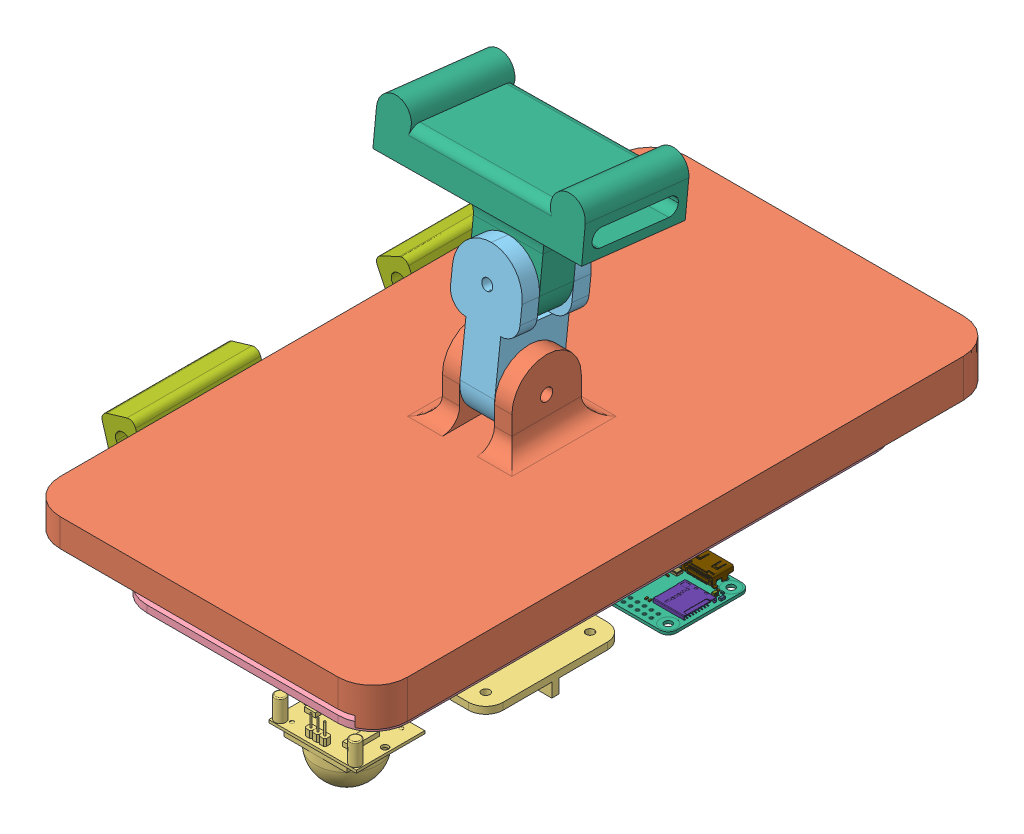
SolidWorks assembly Case_001, configuration Default. Lengths in mm.
Overall size (141.75 176.14 228.6).
95 component instances, 26 part files, 36 mates.
Components (placement in the parent):
- Top_001-2: Top_001 [Default] at (-101.6 0 -203.2) x (0 0 1) z (0 1 0) size (222.25 128.91 71.12) (hidden)
- Battery Mockup-1: Battery Mockup [Default] at (-90.805 45.72 -177.165) x (0 0 1) z (-1 0 0) size (171.45 22.86 80.01)
- Bottom_001-1: Bottom_001 [Default] at (12.7 73.66 12.7) x (-1 0 0) z (0 0 1) size (132.08 39.88 228.6)
- Camera Bracket-1: Camera Bracket [Default] at (-25.4 2.54 -66.675) x (0 0 -1) z (1 0 0) size (50.8 7.62 50.8)
- Separator-1: Separator [Default] at (-3.175 45.72 -3.175) x (0 -1 0) z (1 0 0) size (2.54 196.85 95.25)
- Cam V2.1 v1.step-1: Cam V2.1 v1.step [Default] at (-51.73 11.16 -89.4159) x (0 -1 0) z (1 0 0) size (6.48 24.01 25.01)
- RapberryPiZero.STEP-1: RapberryPiZero.STEP [Default] at (-102.4814 -13.0566 -128.6208) x (-1 0 0) z (0 0 -1) size (65 4.45 31.23)
  - Raspberry_pizero_PCB.STEP-1: Raspberry_pizero_PCB.STEP [Default] at (-51.2564 20.0966 13.0542) size (65 1 30)
  - Micro USB_input_female (short)-SMT.STEP-1: Micro USB_input_female (short)-SMT.STEP [Default] at (-42.3564 22.3216 26.5042) size (7.98 2.94 5.43)
  - Micro USB_input_female (short)-SMT.STEP-2: Micro USB_input_female (short)-SMT.STEP [Default] at (-29.7564 22.3216 26.5042) size (7.98 2.94 5.43)
  - 0204 - Capacitor.STEP-1: 0204 - Capacitor.STEP [Default] at (-62.4121 21.3466 11.2398) size (1 0.5 0.6)
  - 0204 - Capacitor.STEP-2: 0204 - Capacitor.STEP [Default] at (-62.4121 21.3466 12.2528) size (1 0.5 0.6)
  - 0204 - Capacitor.STEP-3: 0204 - Capacitor.STEP [Default] at (-61.8122 21.3466 13.3136) size (1 0.5 0.6)
  - 0204 - Capacitor.STEP-4: 0204 - Capacitor.STEP [Default] at (-61.8122 21.3466 14.2646) size (1 0.5 0.6)
  - 0204 - Capacitor.STEP-5: 0204 - Capacitor.STEP [Default] at (-61.8122 21.3466 15.241) size (1 0.5 0.6)
  - 0204 - Capacitor.STEP-6: 0204 - Capacitor.STEP [Default] at (-61.8122 21.3466 16.2144) size (1 0.5 0.6)
  - 0204 - Capacitor.STEP-7: 0204 - Capacitor.STEP [Default] at (-61.8122 21.3466 17.2416) size (1 0.5 0.6)
  - 0204 - Capacitor.STEP-8: 0204 - Capacitor.STEP [Default] at (-62.5919 21.3466 20.9695) size (1 0.5 0.6)
  - 0204 - Capacitor.STEP-9: 0204 - Capacitor.STEP [Default] at (-62.5919 21.3466 21.919) size (1 0.5 0.6)
  - 0204 - Capacitor.STEP-10: 0204 - Capacitor.STEP [Default] at (-60.4584 21.3466 22.3712) x (0 0 1) z (-1 0 0) size (1 0.5 0.6)
  - 0204 - Capacitor.STEP-11: 0204 - Capacitor.STEP [Default] at (-60.0807 21.3466 22.3712) x (0 0 -1) z (1 0 0) size (1 0.5 0.6)
  - 0204 - Capacitor.STEP-12: 0204 - Capacitor.STEP [Default] at (-59.0466 21.3466 22.3712) x (0 0 -1) z (1 0 0) size (1 0.5 0.6)
  - 0204 - Capacitor.STEP-13: 0204 - Capacitor.STEP [Default] at (-52.6496 21.3466 22.316) x (0 0 1) z (-1 0 0) size (1 0.5 0.6)
  - 0204 - Capacitor.STEP-14: 0204 - Capacitor.STEP [Default] at (-52.25 21.3466 22.316) x (0 0 -1) z (1 0 0) size (1 0.5 0.6)
  - 0204 - Capacitor.STEP-15: 0204 - Capacitor.STEP [Default] at (-51.2398 21.3466 22.316) x (0 0 -1) z (1 0 0) size (1 0.5 0.6)
  - 0204 - Capacitor.STEP-16: 0204 - Capacitor.STEP [Default] at (-49.1841 21.3466 22.316) x (0 0 -1) z (1 0 0) size (1 0.5 0.6)
  - 0204 - Capacitor.STEP-17: 0204 - Capacitor.STEP [Default] at (-48.1448 21.3466 22.316) x (0 0 -1) z (1 0 0) size (1 0.5 0.6)
  - 0204 - Capacitor.STEP-18: 0204 - Capacitor.STEP [Default] at (-46.475 21.3466 21.113) size (1 0.5 0.6)
  - 0204 - Capacitor.STEP-19: 0204 - Capacitor.STEP [Default] at (-45.7322 21.3466 20.0663) size (1 0.5 0.6)
  - 0204 - Capacitor.STEP-20: 0204 - Capacitor.STEP [Default] at (-45.7322 21.3466 19.0675) size (1 0.5 0.6)
  - 0204 - Capacitor.STEP-21: 0204 - Capacitor.STEP [Default] at (-45.7322 21.3466 18.1249) size (1 0.5 0.6)
  - 0204 - Capacitor.STEP-22: 0204 - Capacitor.STEP [Default] at (-45.7322 21.3466 17.1095) size (1 0.5 0.6)
  - 0204 - Capacitor.STEP-23: 0204 - Capacitor.STEP [Default] at (-46.3457 21.3466 16.1412) size (1 0.5 0.6)
  - 0204 - Capacitor.STEP-24: 0204 - Capacitor.STEP [Default] at (-46.3457 21.3466 15.1229) size (1 0.5 0.6)
  - 0204 - Capacitor.STEP-25: 0204 - Capacitor.STEP [Default] at (-46.3457 21.3466 14.0197) size (1 0.5 0.6)
  - 0204 - Capacitor.STEP-26: 0204 - Capacitor.STEP [Default] at (-46.3457 21.3466 12.9589) size (1 0.5 0.6)
  - 0204 - Capacitor.STEP-27: 0204 - Capacitor.STEP [Default] at (-43.6156 21.3466 13.1418) size (1 0.5 0.6)
  - 0204 - Capacitor.STEP-28: 0204 - Capacitor.STEP [Default] at (-43.6156 21.3466 10.1424) size (1 0.5 0.6)
  - 0204 - Capacitor.STEP-29: 0204 - Capacitor.STEP [Default] at (-48.9117 21.3466 7.6917) size (1 0.5 0.6)
  - 0204 - Capacitor.STEP-30: 0204 - Capacitor.STEP [Default] at (-55.4926 21.3466 7.2526) x (0 0 -1) z (1 0 0) size (1 0.5 0.6)
  - 0204 - Capacitor.STEP-31: 0204 - Capacitor.STEP [Default] at (-53.7932 21.3466 7.2526) x (0 0 1) z (-1 0 0) size (1 0.5 0.6)
  - 0204 - Capacitor.STEP-32: 0204 - Capacitor.STEP [Default] at (-59.8477 21.3466 7.2526) x (0 0 1) z (-1 0 0) size (1 0.5 0.6)
  - 0204- Resistor.STEP-1: 0204- Resistor.STEP [Default] at (-43.6109 21.4522 15.4193) x (-1 0 0) z (0 -1 0) size (0.99 0.51 0.36)
  - 0204- Resistor.STEP-2: 0204- Resistor.STEP [Default] at (-43.6109 21.4522 14.4127) x (-1 0 0) z (0 -1 0) size (0.99 0.51 0.36)
  - 0204- Resistor.STEP-3: 0204- Resistor.STEP [Default] at (-43.6109 21.4522 12.4047) x (-1 0 0) z (0 -1 0) size (0.99 0.51 0.36)
  - 0204- Resistor.STEP-4: 0204- Resistor.STEP [Default] at (-42.6936 21.4522 18.4076) x (-1 0 0) z (0 -1 0) size (0.99 0.51 0.36)
  - 0204- Resistor.STEP-5: 0204- Resistor.STEP [Default] at (-39.831 21.4522 18.1462) x (0 0 1) z (0 -1 0) size (0.99 0.51 0.36)
  - 0204- Resistor.STEP-6: 0204- Resistor.STEP [Default] at (-61.8169 21.4522 19.8533) x (-1 0 0) z (0 -1 0) size (0.99 0.51 0.36)
  - 0204- Resistor.STEP-7: 0204- Resistor.STEP [Default] at (-61.8169 21.4522 18.5178) x (-1 0 0) z (0 -1 0) size (0.99 0.51 0.36)
  - 0204- Resistor.STEP-8: 0204- Resistor.STEP [Default] at (-79.148 21.4522 17.7279) x (-1 0 0) z (0 -1 0) size (0.99 0.51 0.36)
  - 0204- Resistor.STEP-9: 0204- Resistor.STEP [Default] at (-56.0985 21.4522 7.2479) x (0 0 -1) z (0 -1 0) size (0.99 0.51 0.36)
  - 0204- Resistor.STEP-10: 0204- Resistor.STEP [Default] at (-28.0827 21.4522 9.5819) x (-1 0 0) z (0 -1 0) size (0.99 0.51 0.36)
  - 0204- Resistor.STEP-11: 0204- Resistor.STEP [Default] at (-21.8613 21.4522 20.9026) x (-1 0 0) z (0 -1 0) size (0.99 0.51 0.36)
  - CAP-0306.STEP-1: CAP-0306.STEP [Default] at (-45.8903 21.4966 8.7634) size (1.6 0.8 0.9)
  - CAP-0306.STEP-2: CAP-0306.STEP [Default] at (-82.0031 21.4966 19.0464) x (0 0 1) z (-1 0 0) size (1.6 0.8 0.9)
  - Raspberry_pizero_BCM2835 with VC4.STEP-1: Raspberry_pizero_BCM2835 with VC4.STEP [Default] at (-54.1608 21.5466 15.1238) x (1 0 0) z (0 0 -1) size (12 0.65 12)
  - Crystal 3.4x2.4mm.STEP-1: Crystal 3.4x2.4mm.STEP [Default] at (-65.3089 21.0966 19.2633) size (3.2 1 2.4)
  - 0204- Resistor.STEP-12: 0204- Resistor.STEP [Default] at (-68.4329 21.4522 5.4384) x (0 0 1) z (0 -1 0) size (0.99 0.51 0.36)
  - 0204- Resistor.STEP-13: 0204- Resistor.STEP [Default] at (-69.7255 21.4522 5.4384) x (0 0 1) z (0 -1 0) size (0.99 0.51 0.36)
  - 0204- Resistor.STEP-14: 0204- Resistor.STEP [Default] at (-65.0626 21.4522 16.5355) x (1 0 0) z (0 -1 0) size (0.99 0.51 0.36)
  - 32,768 Khz Crystal.STEP-1: 32,768 Khz Crystal.STEP [Default] at (-60.5154 21.1428 26.5473) x (0.999848 -0.017452 0) z (0 0 1) size (3.4 1.03 1.5)
  - 0805- Capacitor.STEP-1: 0805- Capacitor.STEP [Default] at (-51.9496 21.9966 5.2384) x (1 0 0) z (0 -1 0) size (2 1.26 0.91)
  - 0805- Capacitor.STEP-2: 0805- Capacitor.STEP [Default] at (-51.9496 21.9966 7.3589) x (1 0 0) z (0 -1 0) size (2 1.26 0.91)
  - 0805- Capacitor.STEP-3: 0805- Capacitor.STEP [Default] at (-37.009 21.9966 22.5384) x (0 0 -1) z (0 -1 0) size (2 1.26 0.91)
  - 0805- Capacitor.STEP-4: 0805- Capacitor.STEP [Default] at (-29.8247 21.9966 13.3538) x (0 0 1) z (0 -1 0) size (2 1.26 0.91)
  - 0805- Capacitor.STEP-5: 0805- Capacitor.STEP [Default] at (-27.9052 21.9966 13.3538) x (0 0 -1) z (0 -1 0) size (2 1.26 0.91)
  - 0805- Capacitor.STEP-6: 0805- Capacitor.STEP [Default] at (-22.8003 21.9966 13.3538) x (0 0 -1) z (0 -1 0) size (2 1.26 0.91)
  - 0805- Capacitor.STEP-7: 0805- Capacitor.STEP [Default] at (-20.9924 21.9966 13.3538) x (0 0 -1) z (0 -1 0) size (2 1.26 0.91)
  - 0204- Resistor.STEP-15: 0204- Resistor.STEP [Default] at (-48.8769 21.4522 23.8207) x (1 0 0) z (0 -1 0) size (0.99 0.51 0.36)
  - 0204- Resistor.STEP-16: 0204- Resistor.STEP [Default] at (-52.4165 21.4522 24.0419) x (1 0 0) z (0 -1 0) size (0.99 0.51 0.36)
  - 0204 - Capacitor.STEP-33: 0204 - Capacitor.STEP [Default] at (-47.1199 21.3466 23.926) x (0 0 1) z (-1 0 0) size (1 0.5 0.6)
  - 0204 - Capacitor Brown.STEP-1: 0204 - Capacitor Brown.STEP [Default] at (-57.5817 21.3466 26.803) size (1 0.5 0.6)
  - 0204 - Capacitor Brown.STEP-2: 0204 - Capacitor Brown.STEP [Default] at (-64.0312 21.3466 26.8794) size (1 0.5 0.6)
  - 0204 - Capacitor Brown.STEP-3: 0204 - Capacitor Brown.STEP [Default] at (-46.3457 21.3466 12.214) size (1 0.5 0.6)
  - 0204 - Capacitor Brown.STEP-4: 0204 - Capacitor Brown.STEP [Default] at (-46.3457 21.3466 11.0963) size (1 0.5 0.6)
  - 0204 - Capacitor Brown.STEP-5: 0204 - Capacitor Brown.STEP [Default] at (-46.3457 21.3466 10.1566) size (1 0.5 0.6)
  - 0204 - Capacitor Brown.STEP-6: 0204 - Capacitor Brown.STEP [Default] at (-43.6156 21.3466 11.1151) size (1 0.5 0.6)
  - 0204 - Capacitor Brown.STEP-7: 0204 - Capacitor Brown.STEP [Default] at (-28.0874 21.3466 10.3236) size (1 0.5 0.6)
  - 0204 - Capacitor Brown.STEP-8: 0204 - Capacitor Brown.STEP [Default] at (-80.6197 21.3466 20.6997) size (1 0.5 0.6)
  - 0204- Resistor.STEP-17: 0204- Resistor.STEP [Default] at (-78.9105 21.4522 21.1554) x (1 0 0) z (0 -1 0) size (0.99 0.51 0.36)
  - 6-Pin SOT.STEP-1: 6-Pin SOT.STEP [Default] at (-79.714 21.0966 19.2138) x (0 0 1) z (0 1 0) size (1.5 1.84 0.95)
  - micro sd molex.STEP-1: micro sd molex.STEP [Default] at (-74.7768 21.6766 -33.0961) x (0 0 1) z (0 1 0) size (11.95 11.4 1.45)
  - hdmi type C.STEP-1: hdmi type C.STEP [Default] at (-71.3564 22.9466 28.6542) size (12.9 4.05 7.7)
  - Voltage Regulator 3x3mm 12-Pin.STEP-1: Voltage Regulator 3x3mm 12-Pin.STEP [Default] at (-23.6842 21.0966 12.6105) x (1 0 0) z (0 1 0) size (3 4.1 1.2)
  - 1210 inductor.STEP-1: 1210 inductor.STEP [Default] at (-46.4963 21.0916 6.3909) x (0 0 1) z (0 1 0) size (3.26 2.79 0.75)
  - 1210 inductor.STEP-2: 1210 inductor.STEP [Default] at (-22.7405 21.0916 9.2394) x (1 0 0) z (0 1 0) size (3.26 2.79 0.75)
  - 1210 inductor.STEP-3: 1210 inductor.STEP [Default] at (-28.2854 21.0916 17.6682) x (1 0 0) z (0 1 0) size (3.26 2.79 0.75)
  - 0204 - Capacitor.STEP-34: 0204 - Capacitor.STEP [Default] at (-48.9117 21.3466 6.5273) size (1 0.5 0.6)
- HCSR501.step-1: HCSR501.step [Default] at (-50.8 6.08 -41.275) x (-1 0 0) z (0 -1 0) size (32 25 25.1)
- Latch-1: Latch [Default] at (-117.1107 62.675 -33.02) x (0.048133 -0.998841 0) z (0 0 1) size (36.83 11.74 35.56)
- Latch-2: Latch [Default] at (-118.5313 61.2626 -134.62) x (0.334291 -0.94247 0) z (0 0 1) size (36.83 11.74 35.56)
- Swivel-1: Swivel [Default] at (-57.15 86.8687 -101.6) x (0 0.993442 -0.114338) z (1 0 0) size (57.15 25.4 25.4)
- Mount-1: Mount [Default] at (-50.8 117.6845 -111.5386) x (-0.00983 0.993394 -0.114332) z (0 0.114338 0.993442) size (57.15 76.2 38.1)
- Upper Latch-1: Upper Latch [Default] at (-104.5164 49.2758 -129.54) x (-0.903606 -0.428364 0) z (0 0 -1) size (12.7 30.48 45.72)
- Upper Latch-2: Upper Latch [Default] at (-106.6984 47.961 -27.94) x (-0.958568 -0.284865 0) z (0 0 -1) size (12.7 30.48 45.72)
Mates (geometry in assembly coordinates):
- Distance1: distance = 2.54 mm anti-aligned: plane of Battery Mockup-1 through (-90.805 68.58 -5.715) normal (0 0 1); plane of Top_001-2 through (-98.425 2.54 -3.175) normal (0 0 -1)
- Coincident1: coincident anti-aligned: plane of Top_001-2 through (-98.425 71.12 198.6207) normal (0 1 0); plane of Bottom_001-1 through (0 71.12 201.7957) normal (0 -1 0)
- Distance2: distance = 0.635 mm anti-aligned: plane of Bottom_001-1 through (-111.76 63.5 -200.66) normal (1 0 0); plane of Top_001-2 through (-111.125 71.12 -200.025) normal (-1 0 0)
- Distance3: distance = 0.635 mm anti-aligned: plane of Bottom_001-1 through (-2.54 63.5 -213.36) normal (0 0 1); plane of Top_001-2 through (-3.175 71.12 -212.725) normal (0 0 -1)
- Coincident4: coincident anti-aligned: plane of Top_001-2 through (-101.6 2.54 -1.4043) normal (0 1 0); plane of Camera Bracket-1 through (-31.75 2.54 90.6707) normal (0 -1 0)
- Coincident5: coincident anti-aligned: plane of Top_001-2 through (-85.725 43.18 14.4707) normal (0 1 0); plane of Separator-1 through (-15.875 43.18 185.9207) normal (0 -1 0)
- Concentric3: concentric anti-aligned: cylinder of Top_001-2 through (-85.725 2.54 185.9207) axis (0 -1 0) radius 12.7; cylinder of Separator-1 through (-85.725 43.18 185.9207) axis (0 1 0) radius 12.7
- Concentric4: concentric anti-aligned: cylinder of Top_001-2 through (-15.875 2.54 185.9207) axis (0 -1 0) radius 12.7; cylinder of Separator-1 through (-15.875 43.18 185.9207) axis (0 1 0) radius 12.7
- Distance4: distance = 7.62 mm anti-aligned: plane of Battery Mockup-1 through (-10.795 68.58 -177.165) normal (1 0 0); plane of Top_001-2 through (-3.175 2.54 -200.025) normal (-1 0 0)
- Coincident7: coincident anti-aligned: plane of Battery Mockup-1 through (-90.805 45.72 24.6307) normal (0 -1 0); plane of Separator-1 through (-15.875 45.72 185.9207) normal (0 1 0)
- Concentric5: concentric aligned: cylinder of Top_001-2 through (-31.75 6.985 128.7707) axis (0 -1 0) radius 2; cylinder of Camera Bracket-1 through (-31.75 10.16 128.7707) axis (0 -1 0) radius 1.5
- Concentric6: concentric aligned: cylinder of Top_001-2 through (-69.85 6.985 128.7707) axis (0 -1 0) radius 2; cylinder of Camera Bracket-1 through (-69.85 10.16 128.7707) axis (0 -1 0) radius 1.5
- Concentric12: concentric anti-aligned: cylinder of Top_001-2 through (-50.8 6.35 160.5207) axis (0 -1 0) radius 12.065; cylinder of HCSR501.step-1 through (-50.8 -0.8505 160.5207) axis (0 1 0) radius 11.4228
- Parallel3: parallel anti-aligned: plane of Top_001-2 through (-3.175 2.54 1.7707) normal (-1 0 0); plane of HCSR501.step-1 through (-34.8 6.08 173.0207) normal (1 0 0)
- Coincident12: coincident anti-aligned: plane of Top_001-2 through (-43.815 5.08 160.5207) normal (0 1 0); plane of HCSR501.step-1 through (-51.2586 5.08 160.7301) normal (0 -1 0)
- Concentric14: concentric anti-aligned: cylinder of Top_001-2 through (-113.03 57.15 211.3207) axis (0 0 -1) radius 1.5; cylinder of Latch-1 through (-113.03 57.15 133.2157) axis (0 0 1) radius 1.5
- Coincident13: coincident anti-aligned: plane of Top_001-2 through (-119.38 63.5 163.6957) normal (0 0 1); plane of Latch-1 through (-109.4995 63.0418 163.6957) normal (0 0 -1)
- Concentric15: concentric anti-aligned: circle of Top_001-2; cylinder of Latch-2 through (-113.03 57.15 31.6157) axis (0 0 1) radius 1.5
- Coincident14: coincident anti-aligned: plane of Top_001-2 through (-119.38 63.5 36.6957) normal (0 0 -1); plane of Latch-2 through (-111.3497 63.8099 36.6957) normal (0 0 1)
- Concentric16: concentric anti-aligned: cylinder of Camera Bracket-1 through (-62.23 2.54 114.8798) axis (0 1 0) radius 1; cylinder of Cam V2.1 v1.step-1 through (-62.23 11.16 114.8798) axis (0 -1 0) radius 1
- Concentric17: concentric anti-aligned: cylinder of Camera Bracket-1 through (-62.23 2.54 102.3798) axis (0 1 0) radius 1; cylinder of Cam V2.1 v1.step-1 through (-62.23 11.16 102.3798) axis (0 -1 0) radius 1
- Coincident15: coincident anti-aligned: plane of Camera Bracket-1 through (-31.75 10.16 90.6707) normal (0 1 0); plane of Cam V2.1 v1.step-1 through (-51.73 10.16 112.3798) normal (0 -1 0)
- Concentric18: concentric anti-aligned: cylinder of Bottom_001-1 through (-63.5 86.8687 100.1957) axis (1 0 0) radius 2.25; cylinder of Swivel-1 through (-44.45 86.8687 100.1957) axis (-1 0 0) radius 2.25
- Coincident16: coincident anti-aligned: plane of Bottom_001-1 through (-57.15 73.66 87.4957) normal (1 0 0); plane of Swivel-1 through (-57.15 86.8687 100.1957) normal (-1 0 0)
- Concentric19: concentric aligned: cylinder of Swivel-1 through (-50.8 119.8626 109.1822) axis (0 -0.114338 -0.993442) radius 12.7; cylinder of Mount-1 through (-50.8 119.1366 102.8739) axis (0 -0.114338 -0.993442) radius 12.7
- Coincident17: coincident anti-aligned: plane of Swivel-1 through (-63.5 131.7533 101.4218) normal (0 -0.114338 -0.993442); plane of Mount-1 through (-50.8 119.1366 102.8739) normal (0 0.114338 0.993442)
- Concentric20: concentric aligned: cylinder of Latch-1 through (-112.7244 50.8074 133.2157) axis (0 0 1) radius 1.6; cylinder of Upper Latch-2 through (-112.7244 50.8074 128.1357) axis (0 0 1) radius 1.5
- Coincident18: coincident anti-aligned: plane of Latch-1 through (-109.4995 63.0418 133.2157) normal (0 0 -1); plane of Upper Latch-2 through (-94.5246 51.5788 133.2157) normal (0 0 1)
- Concentric21: concentric aligned: cylinder of Latch-2 through (-110.9073 51.1653 31.6157) axis (0 0 1) radius 1.6; cylinder of Upper Latch-1 through (-110.9073 51.1653 26.5357) axis (0 0 1) radius 1.5
- Coincident19: coincident anti-aligned: plane of Latch-2 through (-111.3497 63.8099 67.1757) normal (0 0 1); plane of Upper Latch-1 through (-93.0406 54.716 67.1757) normal (0 0 -1)
- Concentric22: concentric aligned: cylinder of Top_001-2 through (-80.225 7.04 71.6207) axis (0 -1 0) radius 2; cylinder of RapberryPiZero.STEP-1/Raspberry_pizero_PCB.STEP-1 through (-80.225 8.04 71.6207) axis (0 -1 0) radius 1.375
- Concentric23: concentric aligned: cylinder of Top_001-2 through (-22.225 7.04 48.6207) axis (0 -1 0) radius 2; cylinder of RapberryPiZero.STEP-1/Raspberry_pizero_PCB.STEP-1 through (-22.225 8.04 48.6207) axis (0 -1 0) radius 1.375
- Coincident20: coincident anti-aligned: plane of Top_001-2 through (-101.6 7.04 -1.4043) normal (0 1 0); plane of RapberryPiZero.STEP-1/Raspberry_pizero_PCB.STEP-1 through (-21.725 7.04 72.1207) normal (0 -1 0)
- Coincident21: coincident anti-aligned: plane of Top_001-2 through (-101.6 0 -203.2) normal (0 -1 0)
- Coincident22: coincident aligned: plane of Top_001-2 through (0 63.5 -203.2) normal (1 0 0)
- Coincident23: coincident aligned: plane of Top_001-2 through (-101.6 63.5 0) normal (0 0 1)
